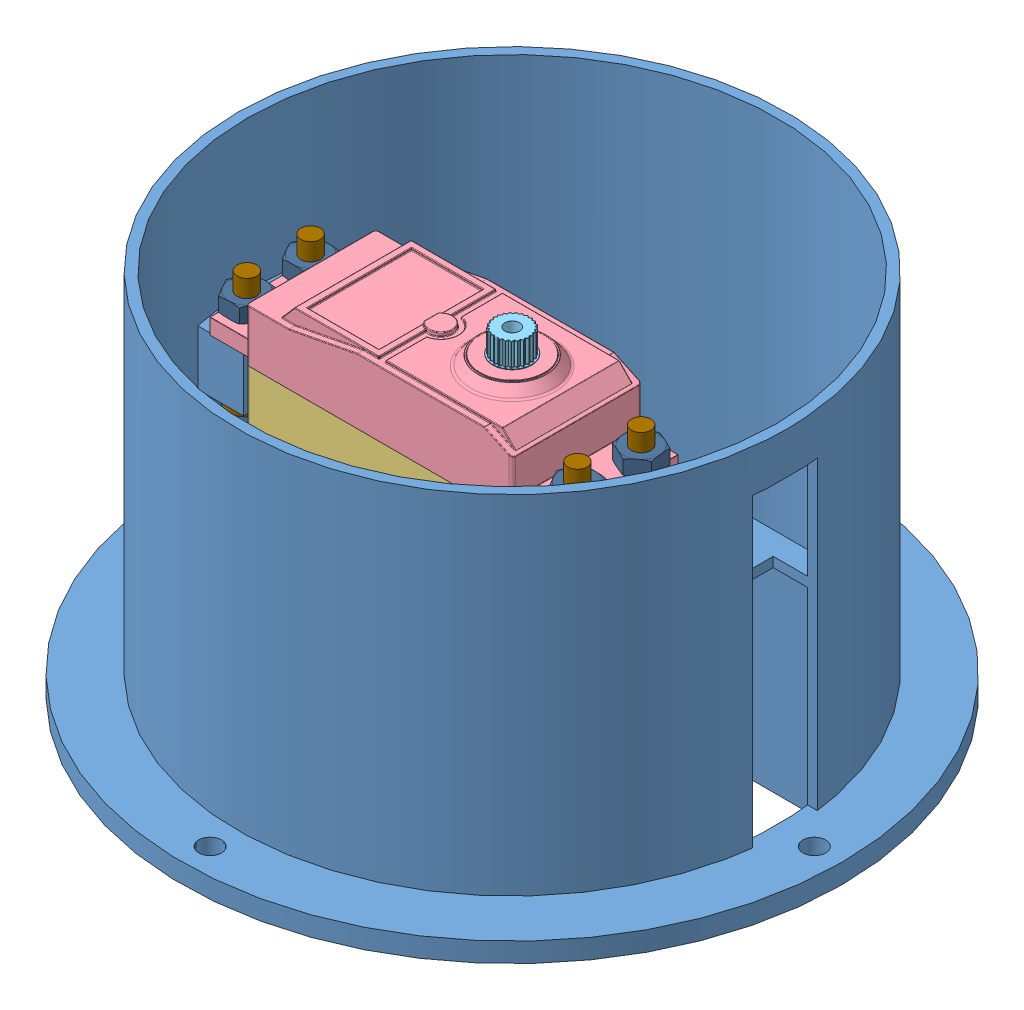
SolidWorks assembly Servo e acoplador, configuration Valor predeterminado. Lengths in mm.
20 component instances, 10 part files, 20 mates.
Components (placement in the parent):
- 28AB - Acoplador Base-Servo-1: 28AB - Acoplador Base-Servo [Valor predeterminado] at (-39.5418 118.5719 71.6403) x (1 0 0) z (0 -1 0) size (101.5 101.5 56.5)
- Servomotor SG 5010-1: Servomotor SG 5010 [Default] at (-47.4323 37.0835 111.5162) x (-1 0 0) z (0 -0.008727 -0.999962) size (57.2 42.11 20.33)
  - Tap 01-1: Tap 01 [Default] at (2.6095 0.3364 39.8745) x (1 0 0) z (0 -0.008727 -0.999962) size (41 6.5 20)
  - Tap 02-1: Tap 02 [Default] at (2.6095 20.3356 39.6999) x (1 0 0) z (0 -0.008727 -0.999962) size (41 20 20)
  - Tap 03-1: Tap 03 [Default] at (2.6095 20.3356 39.6999) x (-1 0 0) z (0 -0.008727 -0.999962) size (54.4 11.9 20)
  - Eje-1: Eje [Default] at (-7.8905 29.3353 39.6214) x (1 0 0) z (0 0.008727 0.999962) size (6 6.5 6)
  - pan head cross recess screw_iso-1: pan head cross recess screw_iso [ISO 7045 - M1.6 x 16 - Z - 16C] at (-15.5814 -5.9305 32.238) x (0 0.999962 -0.008727) z (0.720061 0.006055 0.693884) size (17.27 3.2 3.2)
  - pan head cross recess screw_iso-2: pan head cross recess screw_iso [ISO 7045 - M1.6 x 16 - Z - 16C] at (-15.5814 -5.7963 47.6192) x (0 0.999962 -0.008727) z (0.008727 0.008726 0.999924) size (17.27 3.2 3.2)
  - pan head cross recess screw_iso-3: pan head cross recess screw_iso [ISO 7045 - M1.6 x 16 - Z - 16C] at (20.8004 -5.7963 47.6192) x (0 0.999962 -0.008727) z (0.008727 0.008726 0.999924) size (17.27 3.2 3.2)
  - pan head cross recess screw_iso-4: pan head cross recess screw_iso [ISO 7045 - M1.6 x 16 - Z - 16C] at (20.8004 -5.9305 32.238) x (0 0.999962 -0.008727) z (0.008727 0.008726 0.999924) size (17.27 3.2 3.2)
  - Peça1^Servomotor SG 5010-1: Peça1^Servomotor SG 5010 [Valor predeterminado] at (-17.8905 20.3356 39.6999) x (0 -0.008727 -0.999962) z (-1 0 0) size (7.46 5 7.5) (virtual)
  - Peça2^Servomotor SG 5010-1: Peça2^Servomotor SG 5010 [Valor predeterminado] at (-25.3905 20.3356 39.6999) x (0 -0.008727 -0.999962) z (-1 0 0) size (4.98 1.5 2) (virtual)
- M3x16-1: M3x16 [Default] at (-24.5989 48.5719 76.5403) x (0 1 0) z (0.616396 0 -0.787437) size (18.37 5.6 5.6)
- M3x16-2: M3x16 [Default] at (-75.4847 48.5719 76.5403) x (0 1 0) z (0 0 1) size (18.37 5.6 5.6)
- M3x16-3: M3x16 [Default] at (-24.5989 48.5719 66.7403) x (0 1 0) z (0 0 1) size (18.37 5.6 5.6)
- M3x16-4: M3x16 [Default] at (-75.4847 48.5719 66.7403) x (0 1 0) z (0 0 1) size (18.37 5.6 5.6)
- Porca M3-1: Porca M3 [Default] at (-24.5989 59.4719 66.7403) x (0 1 0) z (0.994335 0 -0.106293) size (2.41 6.36 6.36)
- Porca M3-2: Porca M3 [Default] at (-24.5989 59.4719 76.5403) x (0 1 0) z (0 0 1) size (2.41 6.36 6.36)
- Porca M3-3: Porca M3 [Default] at (-75.4847 59.4719 76.5403) x (0 1 0) z (0 0 1) size (2.41 6.36 6.36)
- Porca M3-4: Porca M3 [Default] at (-75.4847 59.4719 66.7403) x (0 1 0) z (0 0 1) size (2.41 6.36 6.36)
Mates (geometry in assembly coordinates):
- Coincidente1: coincident anti-aligned: plane of 28AB - Acoplador Base-Servo-1 through (-39.5418 57.0719 71.6403) normal (0 1 0); plane of Servomotor SG 5010-1/Tap 03-1 through (-50.0418 57.0719 71.6403) normal (0 -1 0)
- Concêntrico3: concentric aligned: cylinder of 28AB - Acoplador Base-Servo-1 through (-39.5418 57.0719 71.6403) axis (0 1 0) radius 40.75; cylinder of Servomotor SG 5010-1/Eje-1 through (-39.5418 67.0719 71.6403) axis (0 1 0) radius 1.125
- Concêntrico4: concentric anti-aligned: circle of 28AB - Acoplador Base-Servo-1; circle of Servomotor SG 5010-1/Tap 03-1
- Concêntrico5: concentric anti-aligned: circle of 28AB - Acoplador Base-Servo-1; circle of Servomotor SG 5010-1/Tap 03-1
- Concêntrico7: concentric anti-aligned: cylinder of 28AB - Acoplador Base-Servo-1 through (-24.5989 47.0719 76.5403) axis (0 1 0) radius 1.9; cylinder of M3x16-1 through (-24.5989 57.0719 76.5403) axis (0 -1 0) radius 1.5
- Coincidente3: coincident anti-aligned: plane of 28AB - Acoplador Base-Servo-1 through (-39.5418 48.5719 71.6403) normal (0 -1 0); plane of M3x16-1 through (-22.7878 48.5719 77.958) normal (0 1 0)
- Coincidente4: coincident aligned: plane of M3x16-2 through (-77.7847 48.5719 76.5403) normal (0 1 0); plane of M3x16-3 through (-26.8989 48.5719 66.7403) normal (0 1 0)
- Coincidente5: coincident aligned: plane of M3x16-3 through (-26.8989 48.5719 66.7403) normal (0 1 0); plane of M3x16-4 through (-77.7847 48.5719 66.7403) normal (0 1 0)
- Concêntrico8: concentric anti-aligned: cylinder of 28AB - Acoplador Base-Servo-1 through (-75.4847 47.0719 76.5403) axis (0 1 0) radius 1.9; cylinder of M3x16-2 through (-75.4847 57.0719 76.5403) axis (0 -1 0) radius 1.5
- Concêntrico9: concentric anti-aligned: cylinder of 28AB - Acoplador Base-Servo-1 through (-75.4847 47.0719 66.7403) axis (0 1 0) radius 1.9; cylinder of M3x16-4 through (-75.4847 57.0719 66.7403) axis (0 -1 0) radius 1.5
- Concêntrico10: concentric anti-aligned: cylinder of 28AB - Acoplador Base-Servo-1 through (-24.5989 47.0719 66.7403) axis (0 1 0) radius 1.9; cylinder of M3x16-3 through (-24.5989 57.0719 66.7403) axis (0 -1 0) radius 1.5
- Coincidente6: coincident anti-aligned: plane of 28AB - Acoplador Base-Servo-1 through (-39.5418 48.5719 71.6403) normal (0 -1 0); plane of M3x16-2 through (-77.7847 48.5719 76.5403) normal (0 1 0)
- Coincidente7: coincident aligned: plane of Porca M3-3 through (-78.2347 61.8719 76.5403) normal (0 1 0); plane of Porca M3-4 through (-78.2347 61.8719 66.7403) normal (0 1 0)
- Coincidente8: coincident aligned: plane of Porca M3-1 through (-24.3066 61.8719 69.4747) normal (0 1 0); plane of Porca M3-3 through (-78.2347 61.8719 76.5403) normal (0 1 0)
- Coincidente9: coincident aligned: plane of Porca M3-1 through (-24.3066 61.8719 69.4747) normal (0 1 0); plane of Porca M3-2 through (-27.3489 61.8719 76.5403) normal (0 1 0)
- Concêntrico11: concentric aligned: cylinder of M3x16-1 through (-24.5989 57.0719 76.5403) axis (0 -1 0) radius 1.5; cylinder of Porca M3-2 through (-24.5989 61.8719 76.5403) axis (0 -1 0) radius 1.2295
- Concêntrico12: concentric aligned: cylinder of M3x16-3 through (-24.5989 57.0719 66.7403) axis (0 -1 0) radius 1.5; cylinder of Porca M3-1 through (-24.5989 61.8719 66.7403) axis (0 -1 0) radius 1.2295
- Concêntrico13: concentric aligned: cylinder of M3x16-4 through (-75.4847 57.0719 66.7403) axis (0 -1 0) radius 1.5; cylinder of Porca M3-4 through (-75.4847 61.8719 66.7403) axis (0 -1 0) radius 1.2295
- Concêntrico14: concentric aligned: cylinder of M3x16-2 through (-75.4847 57.0719 76.5403) axis (0 -1 0) radius 1.5; cylinder of Porca M3-3 through (-75.4847 61.8719 76.5403) axis (0 -1 0) radius 1.2295
- Coincidente11: coincident anti-aligned: plane of Servomotor SG 5010-1/Tap 03-1 through (-50.0418 59.4719 71.6403) normal (0 1 0); plane of Porca M3-1 through (-24.5989 59.4719 66.7403) normal (0 -1 0)
